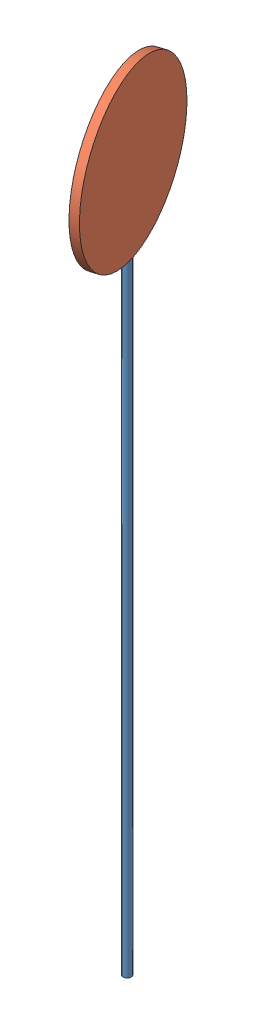
SolidWorks assembly RightSign, configuration Default. Lengths in mm.
Overall size (317.47 1900.15 1611.81).
2 component instances, 2 part files, 2 mates.
Components (placement in the parent):
- Pole-1: Pole [Default] at (243.3466 -98.2392 1407.4383) size (20 1500 20)
- sign-1: sign [Default] at (255.2133 1601.751 1404.8567) x (-0.006358 -0.999978 0.001888) z (-0.952348 0.006631 0.304942) size (400 400 20)
Mates (geometry in assembly coordinates):
- Tangent5: tangent: circle of Pole-1; cylinder of sign-1 through (236.1663 1601.8836 1410.9556) axis (0.952348 -0.006631 -0.304942) radius 200
- Lock2: lock: unknown of Pole-1; unknown of sign-1
